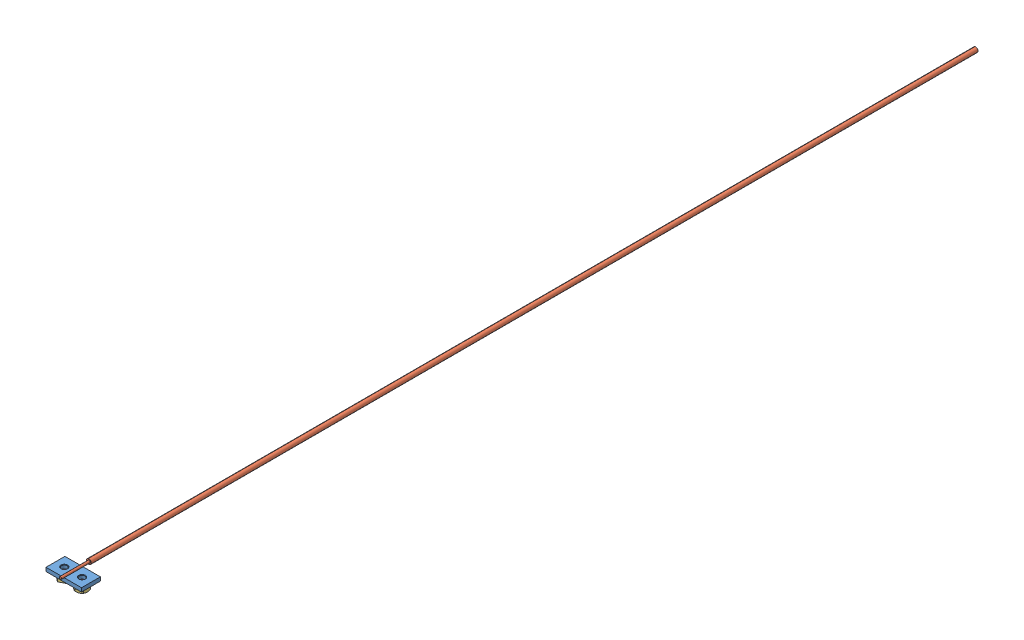
SolidWorks assembly BJ TC outer, configuration Default. Lengths in mm.
Overall size (15 6.85 387).
7 component instances, 5 part files, 11 mates.
Components (placement in the parent):
- BJ TC clamp inner-1: BJ TC clamp inner [default] at (0 62.4125 0) size (15 1.59 8)
- BJ TC straight-1: BJ TC straight [Default] at (0 64.5 5.3715) x (-1 0 0) z (0 0 1) size (2 2 387)
- 2-56 nut MC91841A003-1: 2-56 nut MC91841A003 [91841A003] at (-3.5503 59.8407 0) x (0.38172 0.022647 0.924) z (-0.922378 -0.054724 0.382392) size (4.76 1.59 6.05)
- 2-56 nut MC91841A003-2: 2-56 nut MC91841A003 [91841A003] at (3.6375 61.31 0) x (-0.996113 0.059099 -0.065315) z (-0.0652 0.003868 0.997865) size (4.76 1.59 6.05)
- lock washer 2 MC92146A520-1: lock washer 2 MC92146A520 [92146A520] at (-3.6409 61.3669 0) x (-0.391464 -0.023225 -0.9199) z (0.918286 0.054481 -0.392152) size (4.61 1.12 5.26)
- lock washer 2 MC92146A520-2: lock washer 2 MC92146A520 [92146A520] at (3.7112 62.5531 0) x (-0.9982 0.059223 0.009489) z (0.009472 -0.000562 0.999955) size (4.61 1.12 5.26)
- flat head 2-56 p25 MC91099A104-1: flat head 2-56 p25 MC91099A104 [91099A104] at (3.8364 64.6621 0) x (0.616049 -0.03655 -0.786859) z (0.059225 0.998245 0) size (4.11 4.11 6.52) (hidden)
Mates (geometry in assembly coordinates):
- Concentric5: concentric aligned: circle of 2-56 nut MC91841A003-2; cylinder of lock washer 2 MC92146A520-2 through (3.7112 62.5531 0) axis (-0.059225 -0.998245 0) radius 2.286
- Coincident1: coincident aligned: plane of BJ TC clamp inner-1 through (0 62.4125 0) normal (1 0 0); plane of assembly through (0 0 0) normal (1 0 0)
- Coincident2: coincident aligned: plane of BJ TC clamp inner-1 through (0 62.4125 0) normal (0 0 1); plane of assembly through (0 0 0) normal (0 0 1)
- Coincident6: coincident anti-aligned: plane of BJ TC straight-1; plane of assembly through (0 0 0) normal (1 0 0)
- Concentric11: concentric anti-aligned: circle of flat head 2-56 p25 MC91099A104-1; line of assembly
- Concentric12: concentric aligned: cylinder of lock washer 2 MC92146A520-2 through (3.7112 62.5531 0) axis (-0.059225 -0.998245 0) radius 2.286; circle of flat head 2-56 p25 MC91099A104-1
- Concentric13: concentric aligned: circle of 2-56 nut MC91841A003-2; circle of flat head 2-56 p25 MC91099A104-1
- Concentric15: concentric aligned: cylinder of lock washer 2 MC92146A520-1 through (-3.6409 61.3669 0) axis (-0.059225 0.998245 0) radius 2.286; line of assembly
- Concentric14: concentric aligned: circle of 2-56 nut MC91841A003-1; line of assembly
- Coincident7: coincident: cylinder of BJ TC straight-1 through (0 64.5 5.3715) axis (0 0 -1) radius 0.5; point of assembly
- Tangent1: tangent anti-aligned: plane of BJ TC clamp inner-1 through (0 64 0) normal (0 1 0); cylinder of BJ TC straight-1 through (0 64.5 5.3715) axis (0 0 -1) radius 0.5
